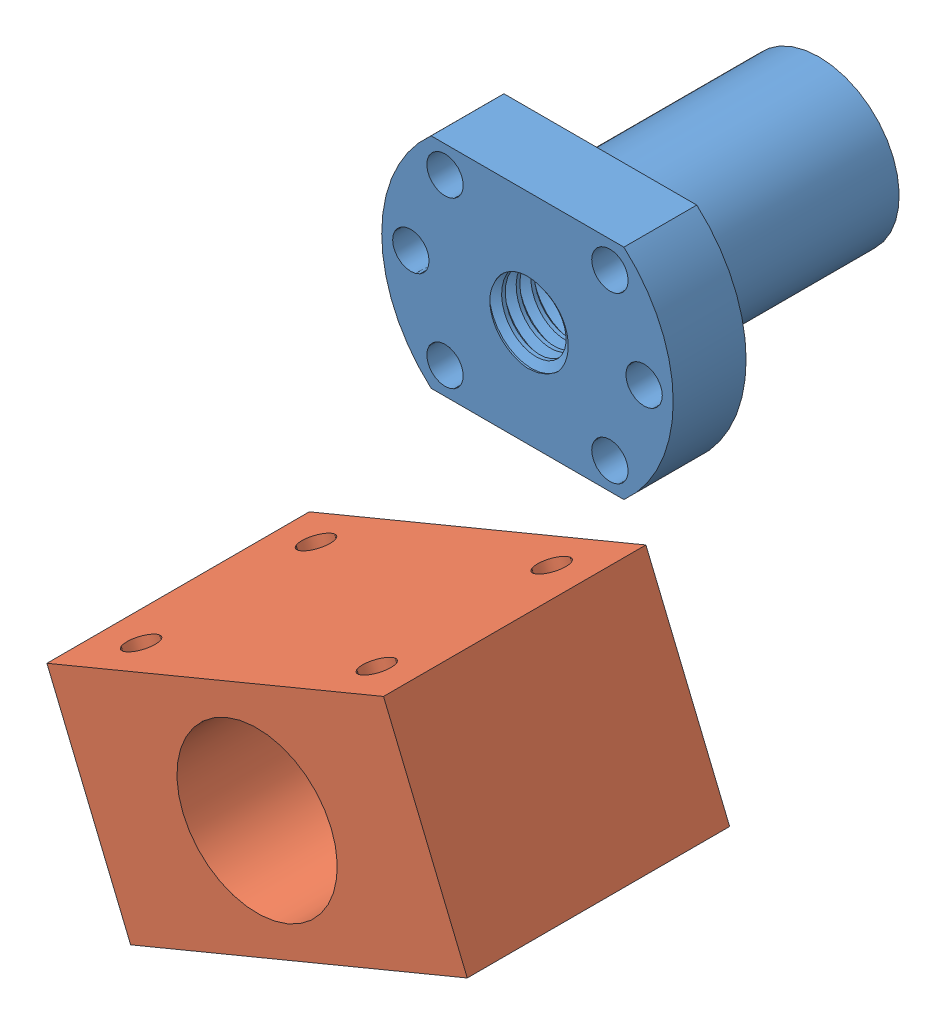
SolidWorks assembly Assem3, configuration Default. Lengths in mm.
Overall size (86.51 46.86 115.64).
4 component instances, 4 part files, 0 mates.
Components (placement in the parent):
- nut-1: nut [Default] at (-23.8133 28.2354 115.5436) x (0 1 0) z (0 0 1) size (30 40 41.74)
- nut seat-1: nut seat [Default] at (13.86 24.6978 200.3164) x (-0.923728 -0.383049 0) z (0 0 -1) size (50 30 36)
- Part8^Assem3-1: Part8^Assem3 [Default] at origin (virtual)
- Part9^Assem3-1: Part9^Assem3 [Default] at origin (virtual)
